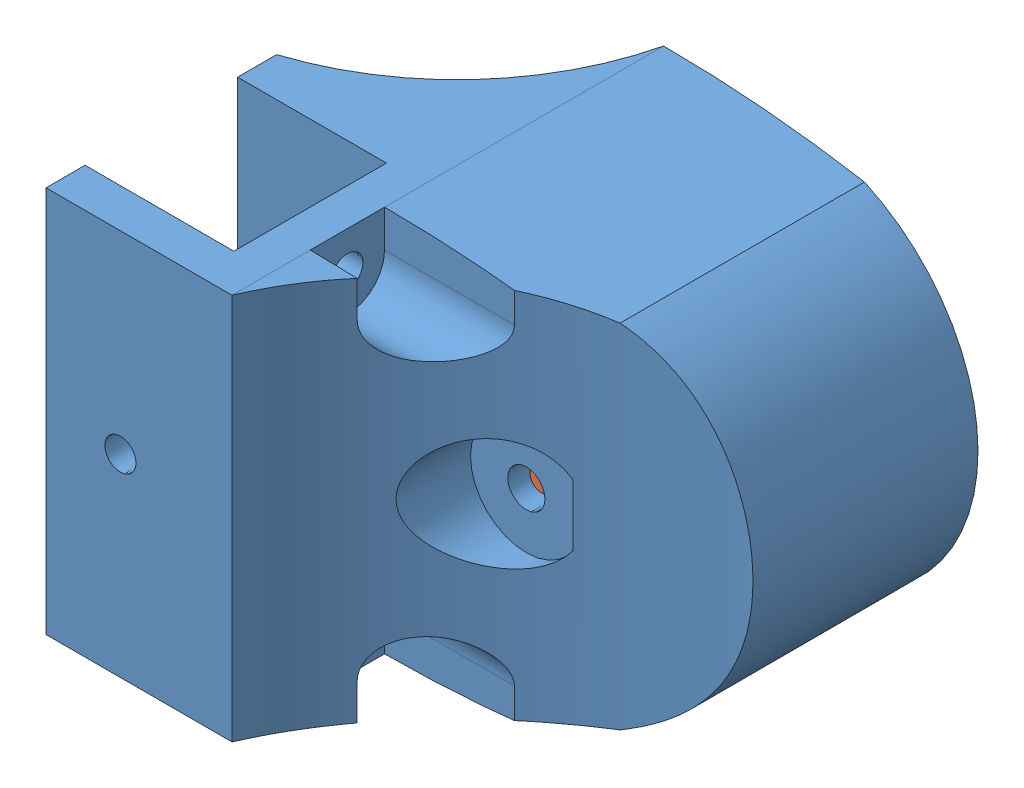
SolidWorks assembly Ролик с креплением, configuration По умолчанию. Lengths in mm.
Overall size (102.91 52 65.67).
3 component instances, 3 part files, 9 mates.
Components (placement in the parent):
- Крепление ролика-1: Крепление ролика [По умолчанию] at (0 26 -31) size (102.91 52 58.37)
- Шпилька-1: Шпилька [По умолчанию] at (41.25 26 -65.3005) size (5 5 40)
- Ролик-1: Ролик [По умолчанию] at (41.25 26 -38.55) x (0 -1 0) z (1 0 0) size (18 9 18)
Mates (geometry in assembly coordinates):
- Совпадение1: coincident aligned: plane of Крепление ролика-1 through (0 26 0) normal (0 0 1); plane of assembly through (0 0 0) normal (0 0 1)
- Совпадение2: coincident anti-aligned: plane of Крепление ролика-1 through (0 0 0) normal (0 -1 0); plane of assembly through (0 0 0) normal (0 1 0)
- Совпадение3: coincident anti-aligned: plane of Крепление ролика-1 through (0 52 0) normal (-1 0 0); plane of assembly through (0 0 0) normal (1 0 0)
- Концентричный1: concentric anti-aligned: cylinder of Крепление ролика-1 through (41.25 26 -58) axis (0 0 1) radius 2.5; cylinder of Шпилька-1 through (41.25 26 -25.3005) axis (0 0 -1) radius 2.5
- Параллельность1: parallel anti-aligned: plane of Крепление ролика-1 through (0 0 0) normal (0 -1 0); plane of Шпилька-1 through (41.25 26 -65.3005) normal (0 1 0)
- Концентричный2: concentric aligned: cylinder of Шпилька-1 through (41.25 26 -25.3005) axis (0 0 -1) radius 2.5; cylinder of Ролик-1 through (41.25 26 -47.55) axis (0 0 -1) radius 2.5
- Совпадение6: coincident: line of Крепление ролика-1 through (47.3 52 -39.35) axis (-1 0 0); plane of Ролик-1 through (41.25 35 -39.35) normal (0 0 -1)
- Совпадение7: coincident: line of Крепление ролика-1 through (35.2 52 -46.75) axis (1 0 0); plane of Ролик-1 through (41.25 32.05 -46.75) normal (0 0 1)
- Параллельность2: parallel anti-aligned: plane of Крепление ролика-1 through (0 52 0) normal (-1 0 0); plane of Ролик-1 through (41.25 26 -38.55) normal (1 0 0)
